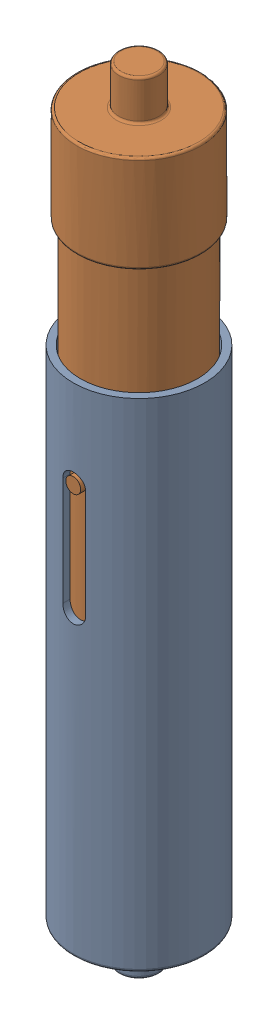
SolidWorks assembly spring, configuration Default. Lengths in mm.
Overall size (23 136.66 23).
2 component instances, 2 part files, 2 mates.
Components (placement in the parent):
- externalspringcasing-1: externalspringcasing [Default] at (-5.997 -35.7873 27.4779) size (23 93.66 23)
- internalspringcasing-1: internalspringcasing [Default] at (-5.997 87.2127 27.4779) x (0 0 1) z (1 0 0) size (22.37 94 21.74)
Mates (geometry in assembly coordinates):
- Concentric1: concentric anti-aligned: cylinder of externalspringcasing-1 through (-5.997 51.2127 27.4779) axis (0 -1 0) radius 10.25; cylinder of internalspringcasing-1 through (-5.997 0.2127 27.4779) axis (0 1 0) radius 10
- Slot1: slot aligned: plane of internalspringcasing-1; plane of externalspringcasing-1 through (-7.997 35.7127 15.9779) normal (1 0 0); cylinder of externalspringcasing-1 through (-5.997 35.7127 15.9779) axis (0 0 1) radius 2
